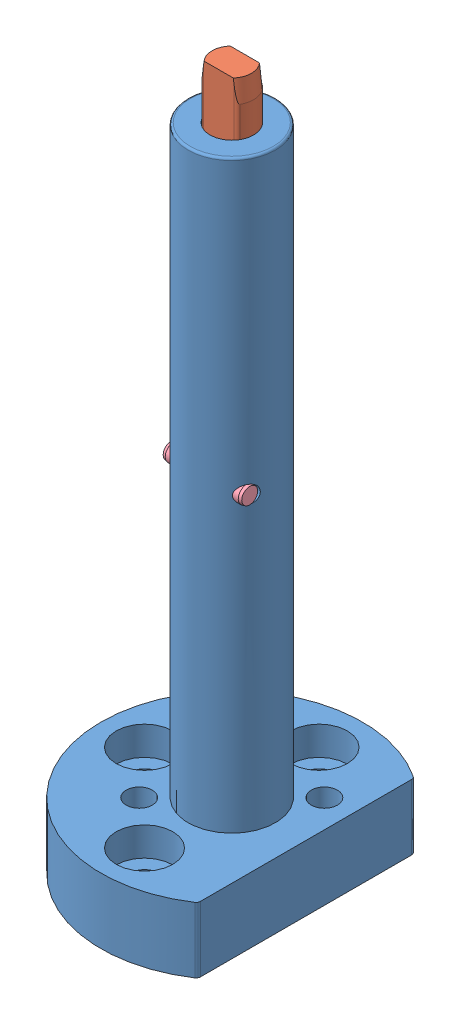
SolidWorks assembly assemb_pino_posi_t1, configuration Default. Lengths in mm.
Overall size (47 161.34 60).
4 component instances, 4 part files, 7 mates.
Components (placement in the parent):
- suporte_posi_t1-1: suporte_posi_t1 [Default] at (55.5939 6.9658 111.8626) size (47 149 60)
- pino_t1-1: pino_t1 [Default] at (55.5939 58.9658 111.8626) x (0 0 1) z (-1 0 0) size (14.5 109 14.5)
- mola_posicionamento-1: mola_posicionamento [Default] at (55.5939 58.9658 111.8626) x (-0.837169 0 -0.546944) z (-0.546944 0 0.837169) size (14.66 52.36 14.64)
- parallel pin hardened_iso-1: parallel pin hardened_iso [ISO 8734 - 4 x 18 - A - St] at (46.7053 88.9658 116.8626) x (1 0 0) z (0 -0.172046 -0.985089) size (18 4 4)
Mates (geometry in assembly coordinates):
- Concentric1: concentric anti-aligned: cylinder of suporte_posi_t1-1 through (55.5939 155.9658 111.8626) axis (0 -1 0) radius 10; cylinder of pino_t1-1 through (55.5939 167.9658 111.8626) axis (0 1 0) radius 5
- Coincident1: coincident anti-aligned: plane of suporte_posi_t1-1 through (55.5939 63.9658 111.8626) normal (0 -1 0); plane of pino_t1-1 through (55.5939 63.9658 119.1126) normal (0 1 0)
- Concentric3: concentric aligned: cylinder of suporte_posi_t1-1 through (55.5939 63.9658 111.8626) axis (0 -1 0) radius 7.25; circle of mola_posicionamento-1
- Coincident2: coincident aligned: plane of pino_t1-1 through (55.5939 58.9658 111.8626) normal (0 -1 0); circle of mola_posicionamento-1
- Perpendicular1: perpendicular: plane of suporte_posi_t1-1 through (72.5939 21.9658 136.5811) normal (1 0 0); plane of pino_t1-1 through (59.5939 162.9658 114.8626) normal (0 0 1)
- Concentric4: concentric aligned: cylinder of suporte_posi_t1-1 through (25.5939 88.9658 116.8626) axis (1 0 0) radius 2; cone of parallel pin hardened_iso-1 through (64.7053 88.9658 116.8626) axis (1 0 0)
- Concentric5: concentric anti-aligned: cylinder of suporte_posi_t1-1 through (25.5939 88.9658 116.8626) axis (1 0 0) radius 2; cylinder of parallel pin hardened_iso-1 through (40.3553 88.9658 116.8626) axis (-1 0 0) radius 2
